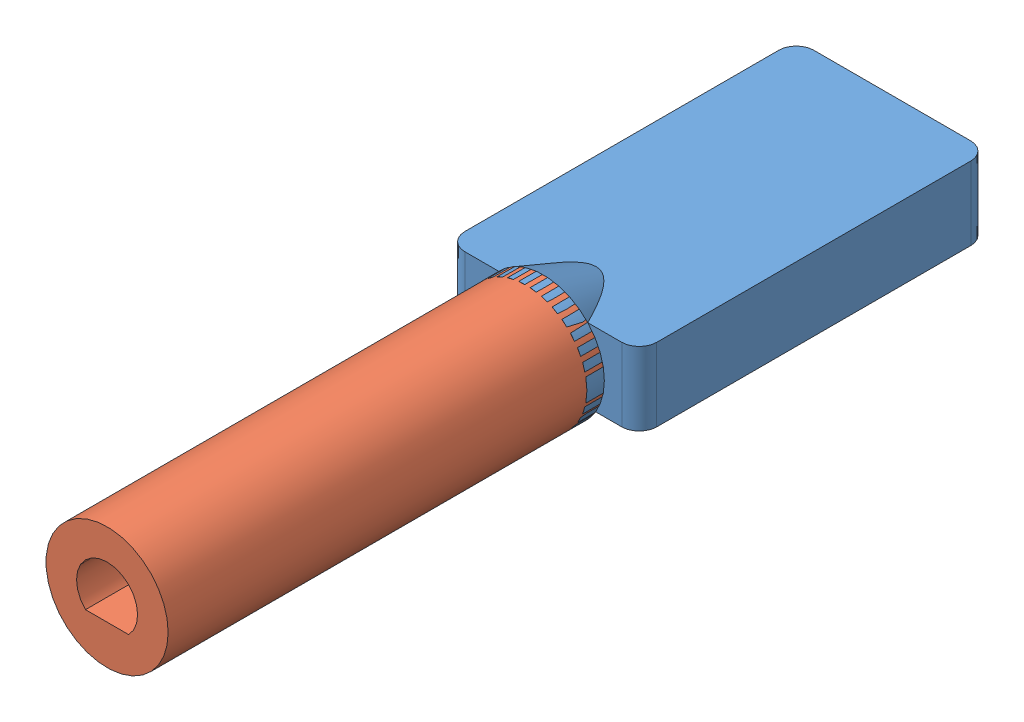
SolidWorks assembly porta forchetta acciaio, configuration Default. Lengths in mm.
Overall size (11 7 45).
2 component instances, 2 part files, 2 mates.
Components (placement in the parent):
- alloggio forchetta acciaio-1: alloggio forchetta acciaio [Default] at (8.3587 12.7041 14.6593) size (11 7 21)
- alloggio forchetta legno-1: alloggio forchetta legno [Default] at (8.3587 13.3041 49.6593) x (-1 0 0) z (0 0 -1) size (7 7 25)
Mates (geometry in assembly coordinates):
- Coincident1: coincident anti-aligned: axis of alloggio forchetta acciaio-1 through (8.3587 13.3041 24.6593) axis (0 0 -1); axis of alloggio forchetta legno-1 through (8.3587 13.3041 24.6593) axis (0 0 1)
- Coincident2: coincident anti-aligned: plane of alloggio forchetta acciaio-1 through (8.3587 14.5041 24.6593) normal (0 0 1); plane of alloggio forchetta legno-1 through (8.3587 13.3041 24.6593) normal (0 0 -1)
